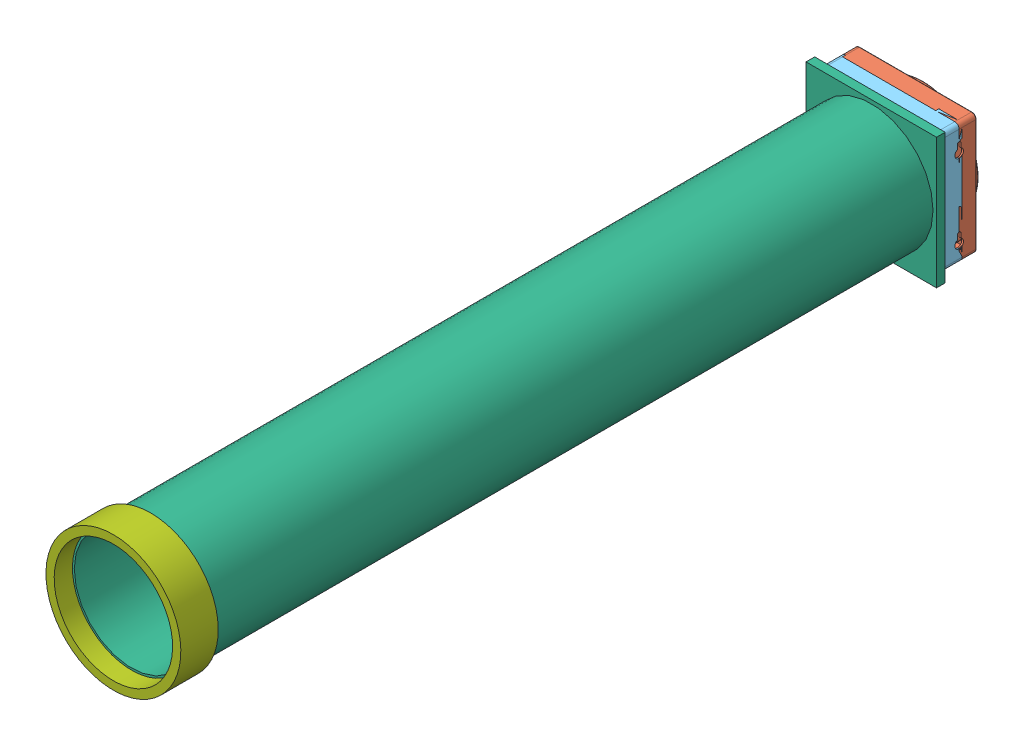
SolidWorks assembly Assembly Main, configuration Default. Lengths in mm.
Overall size (201.76 192.93 930.5).
10 component instances, 9 part files, 13 mates.
Components (placement in the parent):
- ping pong ball-2: ping pong ball [Default] at (49.426 74.2264 690.6006) x (0.790569 -0.000883 0.612372) z (-0.587021 0.283664 0.758249) size (130 130 130)
- Assembly Mini DC Fan-2: Assembly Mini DC Fan [Default] at origin size (139 139 57.5)
  - box_back-1: box_back [Default] at (49.426 74.2264 98.3448) size (139 139 33)
  - impeller-1: impeller [Default] at (49.426 74.2264 140.3448) x (-0.036359 0.999339 0) z (0 0 1) size (128.05 126.85 47.77)
  - pemegang-1: pemegang [Default] at (49.426 74.2264 90.3448) x (0.5 0.866025 0) z (0 0 1) size (36.14 36.7 6.6)
  - box_front-1: box_front [Default] at (49.426 74.2264 139.8448) x (-1 0 0) z (0 0 -1) size (139 139 38)
- Glass tube-3: Glass tube [Default] at (49.426 74.2264 999.8448) x (0 -1 0) z (1 0 0) size (150 860 150)
- Part1^Assembly Main-1: Part1^Assembly Main [Default] at origin (virtual)
- Part2^Assembly Main-1: Part2^Assembly Main [Default] at (49.426 74.2264 999.8448) x (0 1 0) z (0 0 1) (virtual)
- sensor holder-1: sensor holder [Default] at (49.426 74.2264 977.8448) x (-0.958034 -0.286656 0) z (-0.286656 0.958034 0) size (155 43 155)
Mates (geometry in assembly coordinates):
- Coincident4: coincident anti-aligned: plane of Assembly Mini DC Fan-2/box_front-1 through (113.926 9.7264 139.8448) normal (0 0 1); plane of Glass tube-3 through (49.426 74.2264 139.8448) normal (0 0 -1)
- Concentric2: concentric aligned: circle of Assembly Mini DC Fan-2/box_front-1; circle of Glass tube-3
- InPlace1: in place: plane of ? through (-224.9887 221.2184 1357.0125) normal (0 0 1); plane of ? through (0 0 1357.0125) normal (0 0 1); moOrthogonalPlaneRef_w of ? through (-224.9887 221.2184 1357.0125) normal (0 0 1); plane of ? through (0 0 1357.0125) normal (0 1 0); plane of ? through (-224.9887 221.2184 1357.0125) normal (0 0 1); plane of ? through (0 0 1357.0125) normal (1 0 0); plane of Glass tube-3 through (49.426 74.2264 999.8448) normal (0 0 1); unknown of Part2^Assembly Main-1
- Coincident5: coincident aligned: plane of Glass tube-3; plane of Part2^Assembly Main-1
- Coincident6: coincident aligned: moOrthogonalPlaneRef_w of Glass tube-3; plane of Part2^Assembly Main-1 through (49.426 74.2264 999.8448) normal (-1 0 0)
- Coincident7: coincident anti-aligned: moOrthogonalPlaneRef_w of Glass tube-3 through (74.2264 999.8448 0) axis (-1 0 0); plane of Part2^Assembly Main-1 through (49.426 74.2264 999.8448) normal (0 1 0)
- Concentric3: concentric aligned: circle of Glass tube-3; circle of sensor holder-1
- Coincident8: coincident anti-aligned: plane of Glass tube-3 through (49.426 74.2264 999.8448) normal (0 0 1); plane of sensor holder-1 through (49.426 74.2264 999.8448) normal (0 0 -1)
- Concentric4: concentric: sphere of ping pong ball-2; cylinder of Glass tube-3 through (49.426 74.2264 149.8448) axis (0 0 1) radius 66
- Parallel2: parallel aligned: plane of Assembly Mini DC Fan-2/box_front-1 through (-20.074 138.7264 114.8448) normal (-1 0 0); plane of Glass tube-3 through (-25.574 149.2264 139.8448) normal (-1 0 0)
- Coincident12: coincident aligned: plane of Assembly Mini DC Fan-2 through (0 0 0) normal (0 0 1)
- Coincident13: coincident aligned: plane of Assembly Mini DC Fan-2 through (0 0 0) normal (0 1 0)
- Coincident15: coincident aligned: plane of Assembly Mini DC Fan-2 through (0 0 0) normal (1 0 0)
